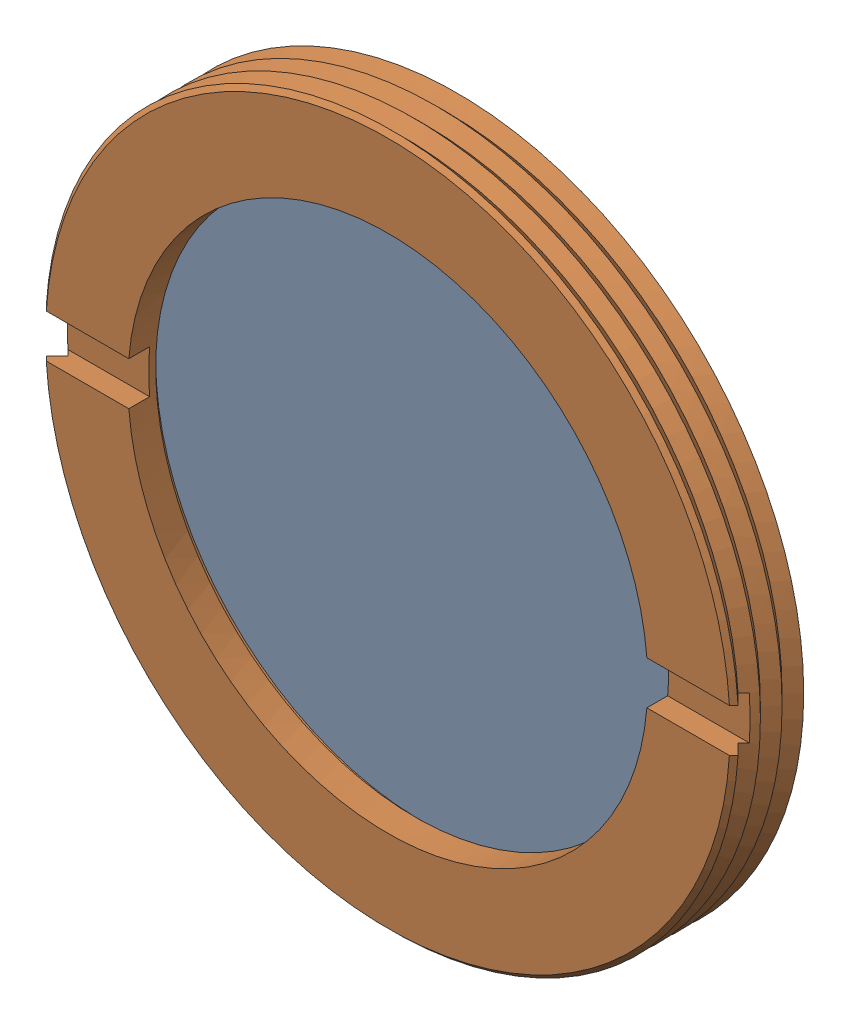
SolidWorks assembly 100097A-IR FILTER ASSEMBLY 0.75 INCH, configuration Default. Lengths in mm.
Overall size (25.4 25.4 2.54).
2 component instances, 2 part files, 0 mates.
Components (placement in the parent):
- 440002-IR CUT FILTER 22MM DIA-1: 440002-IR CUT FILTER 22MM DIA [Default] at (0 0 0.27) size (22 22 1)
- 110054AB-IR FILTER SUPPORT-1: 110054AB-IR FILTER SUPPORT [Default] at origin size (25.4 25.4 2.54)
